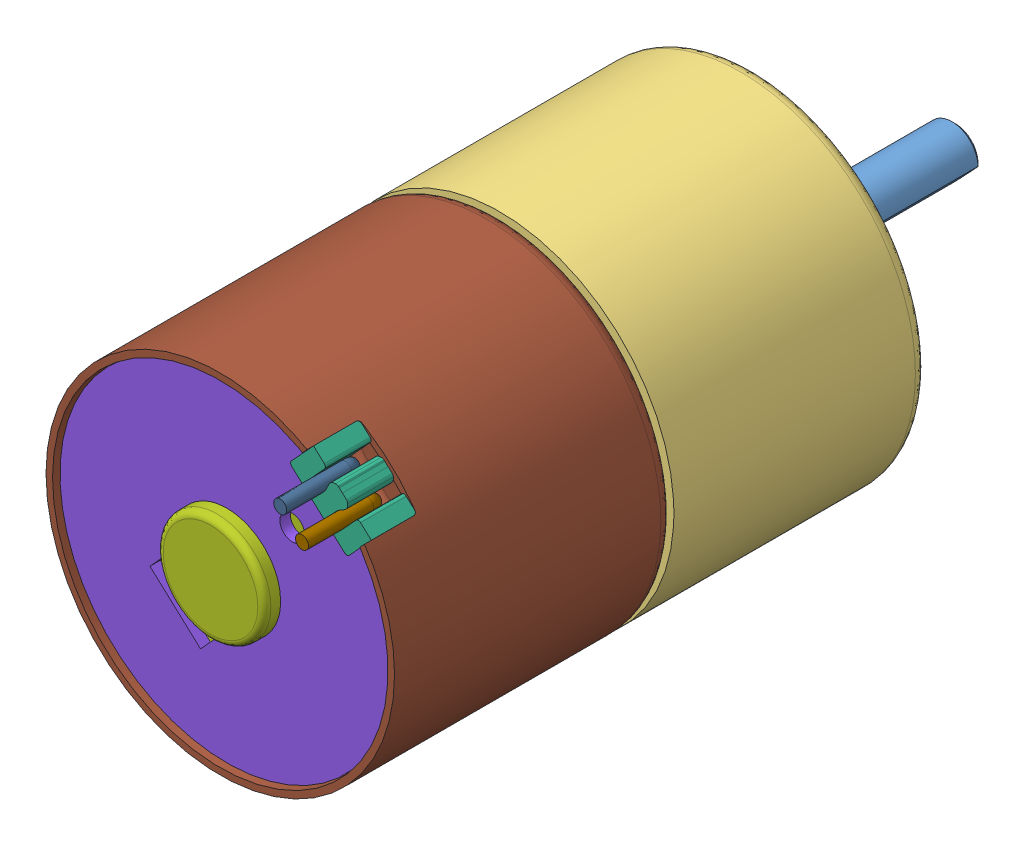
SolidWorks assembly Mclennan 1271-2stage, configuration Default. Lengths in mm.
Overall size (35.81 35.79 58.55).
17 component instances, 11 part files, 0 mates.
Components (placement in the parent):
- Mclennan 1271-2stage.stp-1: Mclennan 1271-2stage.stp [Default] at origin size (35.81 35.79 58.55)
  - Gearbox assy.stp-1: Gearbox assy.stp [Default] at (-178.9442 -59.8542 442.6707) size (26.7 26.7 34.9)
    - Shaft.stp-1: Shaft.stp [Default] at (0 0 -28.3) size (3.99 3.99 11.5)
    - M3 insert.stp-1: M3 insert.stp [Default] at (0 10 -14.4) size (4 4 5)
    - M3 insert.stp-2: M3 insert.stp [Default] at (0 -10 -14.4) size (4 4 5)
    - Gearbox.stp-1: Gearbox.stp [Default] at (0 0 -50) size (26.7 26.7 23.8)
    - Screw _ Fillister - M2.5 x 50.0.stp-1: Screw _ Fillister - M2.5 x 50.0.stp [Default] at origin size (3.86 3.86 2.15)
    - Screw _ Fillister - M2.5 x 50.0-0.stp-1: Screw _ Fillister - M2.5 x 50.0-0.stp [Default] at (7.95 0 -10.7) x (1 0 0) z (0 0 -1) size (3.86 3.86 2.15)
  - Body assy.stp-1: Body assy.stp [Default] at (-178.9442 -59.8542 447.7707) size (35.81 35.79 23.65)
    - End plate assy.stp-1: End plate assy.stp [Default] at origin size (35.81 35.79 6.25)
      - Insulators.stp-1: Insulators.stp [Default] at origin size (35.81 35.79 4.75)
        - Wire insulator.stp-1: Wire insulator.stp [Default] at (21.3671 7.764 28.0313) x (-0.674951 -0.737862 0) z (0 0 1) size (2.75 6 3.5)
        - Insulator.stp-1: Insulator.stp [Default] at (0 0 22.15) x (0.737862 -0.674951 0) z (0 0 -1) size (25.51 25.17 2.55)
      - End plate.stp-1: End plate.stp [Default] at (0 0 10.9) size (25.55 25.55 0.8)
      - Red wire.stp-1: Red wire.stp [Default] at (8.5082 7.501 18.65) x (0.707107 -0.707107 0) z (0 0 1) size (1.08 2.27 6.25)
      - Green wire.stp-1: Green wire.stp [Default] at (4.7521 7.2996 20.5725) size (2.05 2.13 6.25)
    - Body.stp-1: Body.stp [Default] at origin size (26.7 26.7 21.4)
